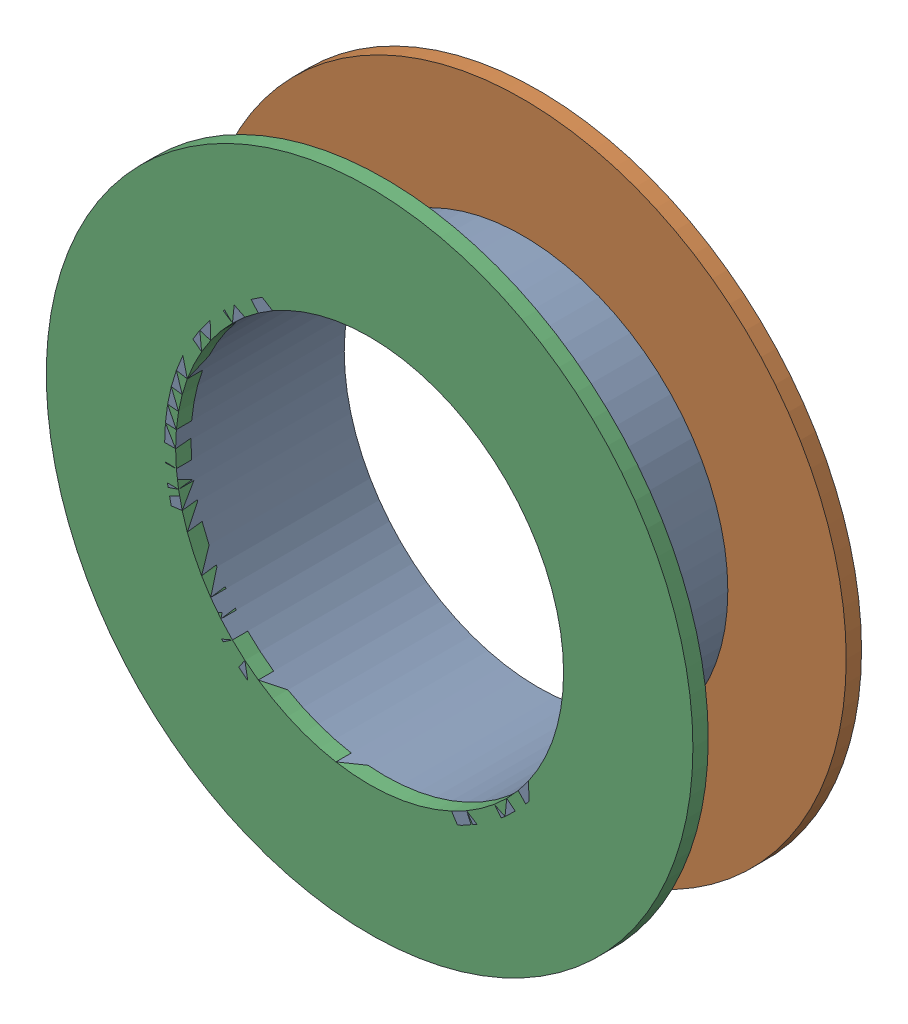
SolidWorks assembly Pad UART-2(15.54mm,43.4mm) on Multi-Layer, configuration Predeterminado. Lengths in mm.
Overall size (1.5 1.5 0.39).
6 component instances, 2 part files, 0 mates.
Components (placement in the parent):
- Pad Hole-1-1: Pad Hole-1 [Predeterminado] at (15.54 43.4 -0.4013) size (0.95 0.95 0.39)
  - Pad Hole-Part-1-1-1: Pad Hole-Part-1-1 [Predeterminado] at origin size (0.95 0.95 0.39)
- Top Layer-1-1: Top Layer-1 [Predeterminado] at (15.54 43.4 -0.4013) size (1.5 1.5 0.04)
  - Top Layer-Part-1-1-1: Top Layer-Part-1-1 [Predeterminado] at origin size (1.5 1.5 0.04)
- Top Layer-1-2: Top Layer-1 [Predeterminado] at (15.54 43.4 -0.0457) size (1.5 1.5 0.04)
  - Top Layer-Part-1-1-1: Top Layer-Part-1-1 [Predeterminado] at origin size (1.5 1.5 0.04)
